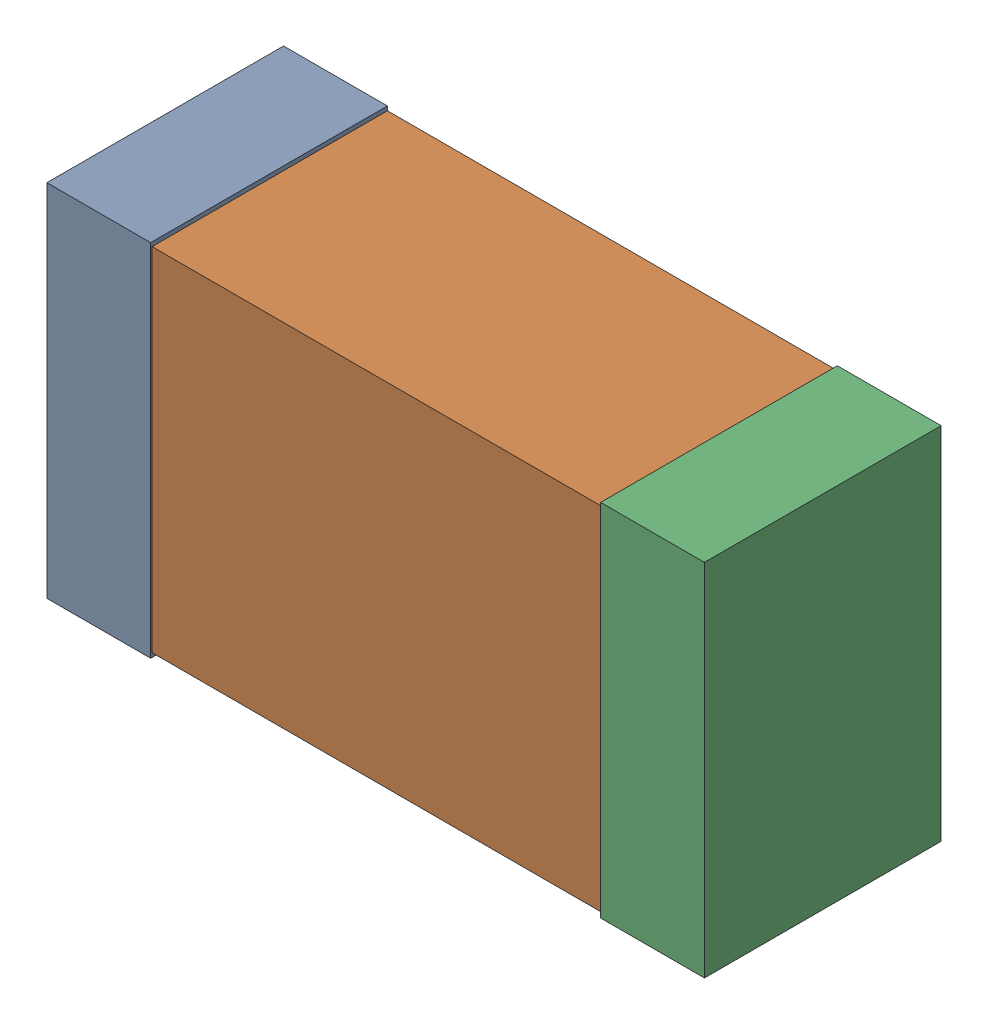
SolidWorks assembly R7Kanaloa_v2.0.0_Motor, configuration Default. Lengths in mm.
Overall size (2.38 1.3 0.85).
6 component instances, 2 part files, 0 mates.
Components (placement in the parent):
- 352877648-1: 352877648 [Default] at (57.928 114.8862 0) size (0.38 1.3 0.85)
  - Extruded_14-1: Extruded_14 [Default] at origin size (0.38 1.3 0.85)
- 352877904-1: 352877904 [Default] at (58.928 114.8862 0) size (2.2 1.27 0.85)
  - Extruded_18-1: Extruded_18 [Default] at origin size (2.2 1.27 0.85)
- 352877648-2: 352877648 [Default] at (59.928 114.8862 0) size (0.38 1.3 0.85)
  - Extruded_14-1: Extruded_14 [Default] at origin size (0.38 1.3 0.85)
